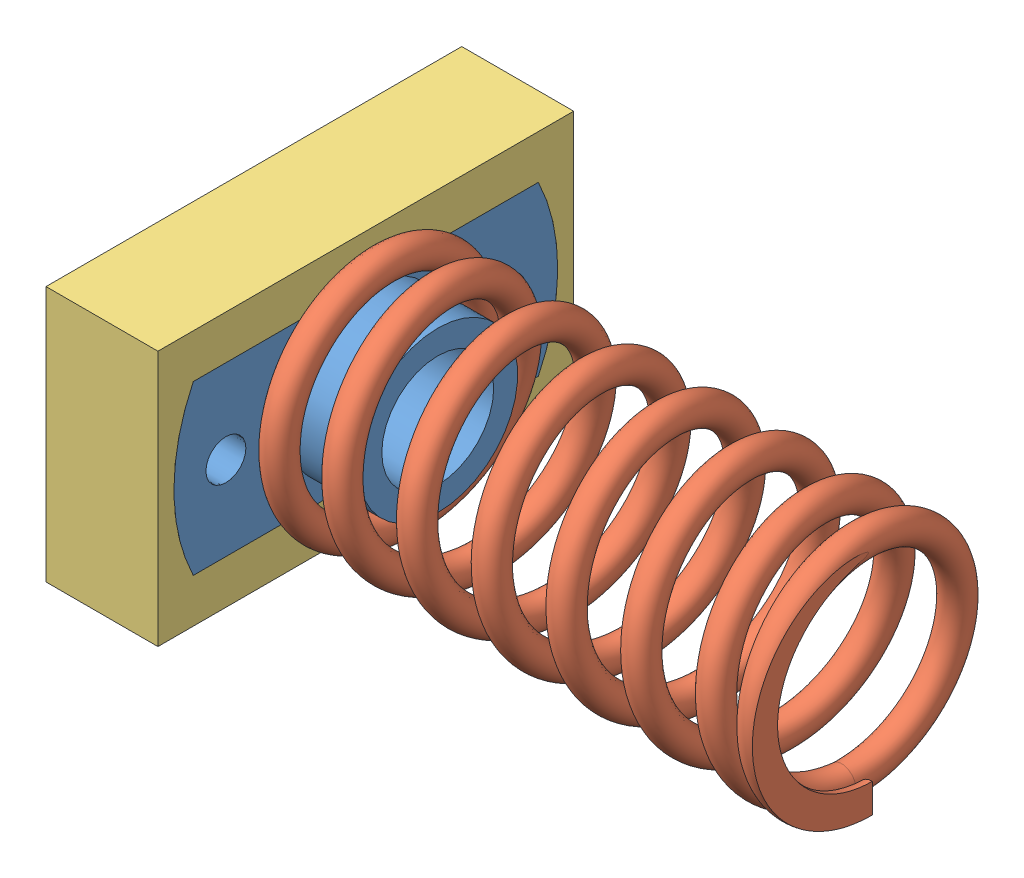
SolidWorks assembly spring mech, configuration Default. Lengths in mm.
Overall size (38.75 16.14 26).
3 component instances, 3 part files, 4 mates.
Components (placement in the parent):
- leadnut-1: leadnut [Default] at (-36.9744 6.5573 8.9533) x (-1 0 0) z (0 -1 0) size (10 24 10.5)
- 9434K135_MUSIC-WIRE STEEL COMPRESSION SPRINGS-1: 9434K135_MUSIC-WIRE STEEL COMPRESSION SPRINGS [9434K135] at (-41.4744 6.4644 9.0297) x (0 -1 0) z (0 0 1) size (15.72 32.66 15.84)
- UOM20-4P038-1: UOM20-4P038 [Default] at (-41.4744 -1.4427 21.9533) x (0 1 0) z (-1 0 0) size (16 26 7)
Mates (geometry in assembly coordinates):
- Coincident13: coincident anti-aligned: plane of leadnut-1 through (-41.4744 6.5573 3.9533) normal (1 0 0); plane of 9434K135_MUSIC-WIRE STEEL COMPRESSION SPRINGS-1 through (-41.4744 14.0844 1.4096) normal (-1 0 0)
- Lock1: lock: unknown of leadnut-1; unknown of 9434K135_MUSIC-WIRE STEEL COMPRESSION SPRINGS-1
- Coincident14: coincident anti-aligned: plane of leadnut-1 through (-44.9744 6.5573 -3.0467) normal (-1 0 0); plane of guide block-1 through (-44.9744 -1.4427 21.9533) normal (1 0 0)
- Concentric2: concentric aligned: cylinder of leadnut-1 through (-9.7481 6.5573 8.9533) axis (1 0 0) radius 5; cylinder of guide block-1 through (-48.4744 6.5573 8.9533) axis (1 0 0) radius 5
